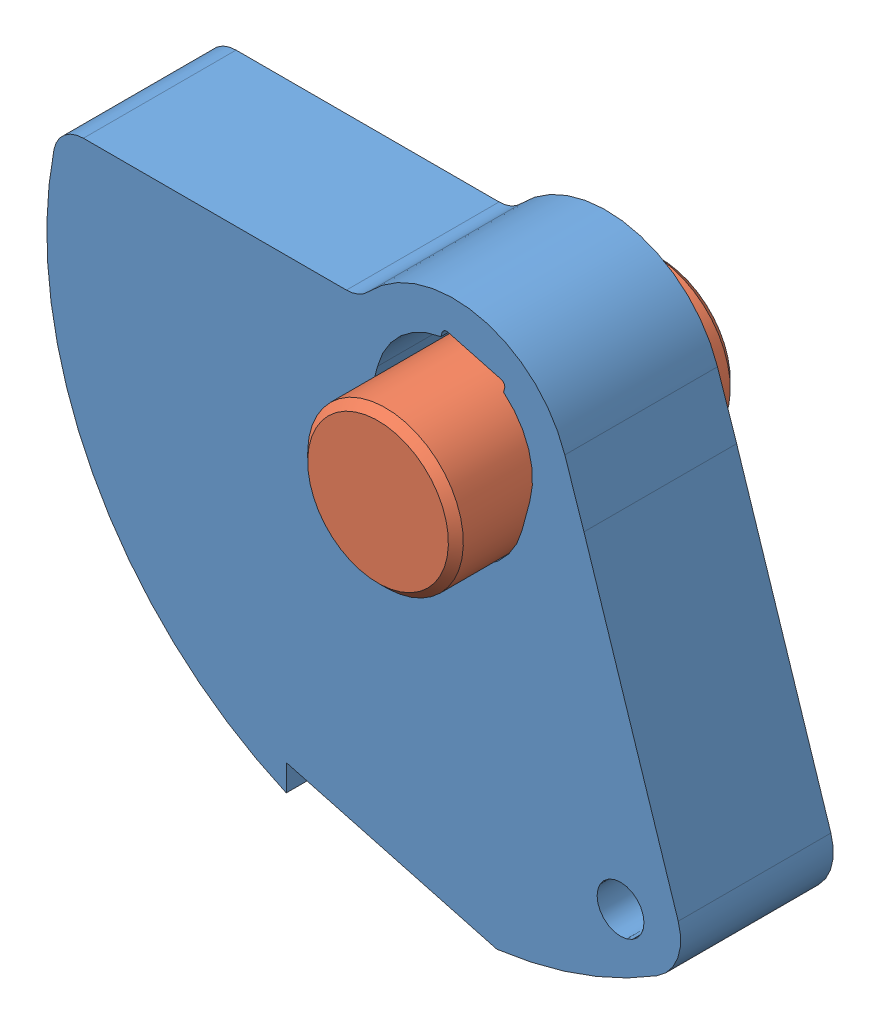
SolidWorks assembly Shaved Down Swingbolt Assembly, configuration Default. Lengths in mm.
Overall size (32.27 27.59 14.35).
3 component instances, 3 part files, 2 mates.
Components (placement in the parent):
- Swingbolt Shaved Down-1: Swingbolt Shaved Down [Default] at (11.7373 20.2148 23.4314) size (32.27 27.59 7.77)
- 4105-1: 4105 [Default] at (11.7373 20.2148 12.5366) x (-0.965224 0.261425 0) z (0.261425 0.965224 0) size (7.92 14.35 7.92)
- 2979-1: 2979 [Default] at (10.625 15.9504 19.7189) x (0.258819 0.965926 0) z (0 0 1) size (11.38 3.26 3.28)
Mates (geometry in assembly coordinates):
- Coincident2: coincident anti-aligned: plane of Swingbolt Shaved Down-1 through (13.1967 25.6614 15.659) normal (-0.258819 -0.965926 0); plane of 2979-1 through (13.225 25.6538 19.7189) normal (0.258819 0.965926 0)
- Concentric1: concentric anti-aligned: cylinder of Swingbolt Shaved Down-1 through (11.7373 20.2148 15.659) axis (0 0 1) radius 4.0132; cylinder of 4105-1 through (11.7373 20.2148 26.8876) axis (0 0 -1) radius 3.9624
